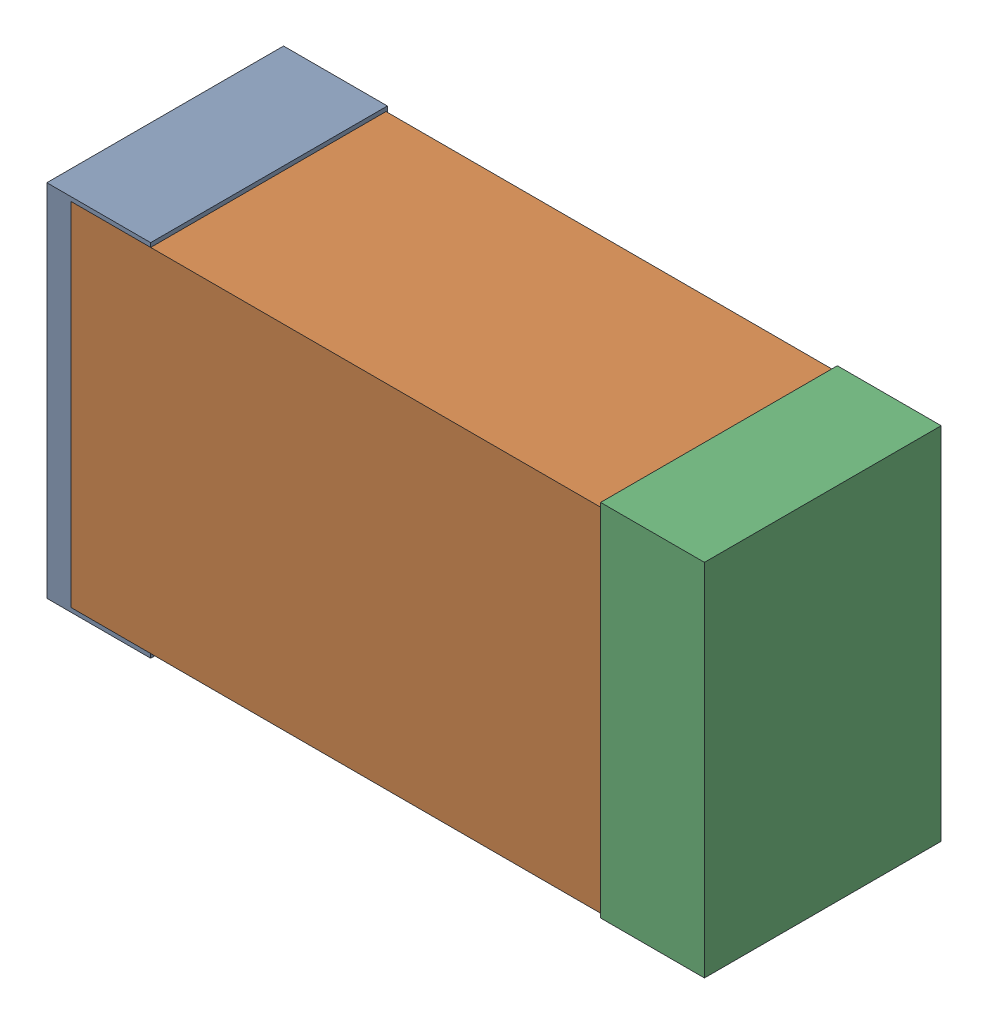
SolidWorks assembly USB67_C11, configuration Default. Lengths in mm.
Overall size (2.38 1.3 0.85).
6 component instances, 2 part files, 0 mates.
Components (placement in the parent):
- 384311232-1: 384311232 [Default] at (150.384 88.646 -1.9574) size (0.38 1.3 0.85)
  - Extruded_8-1: Extruded_8 [Default] at origin size (0.38 1.3 0.85)
- 402662800-1: 402662800 [Default] at (151.384 88.646 -1.9524) size (2.2 1.27 0.85)
  - Extruded_30-1: Extruded_30 [Default] at origin size (2.2 1.27 0.85)
- 384311232-2: 384311232 [Default] at (152.384 88.646 -1.9574) size (0.38 1.3 0.85)
  - Extruded_8-1: Extruded_8 [Default] at origin size (0.38 1.3 0.85)
